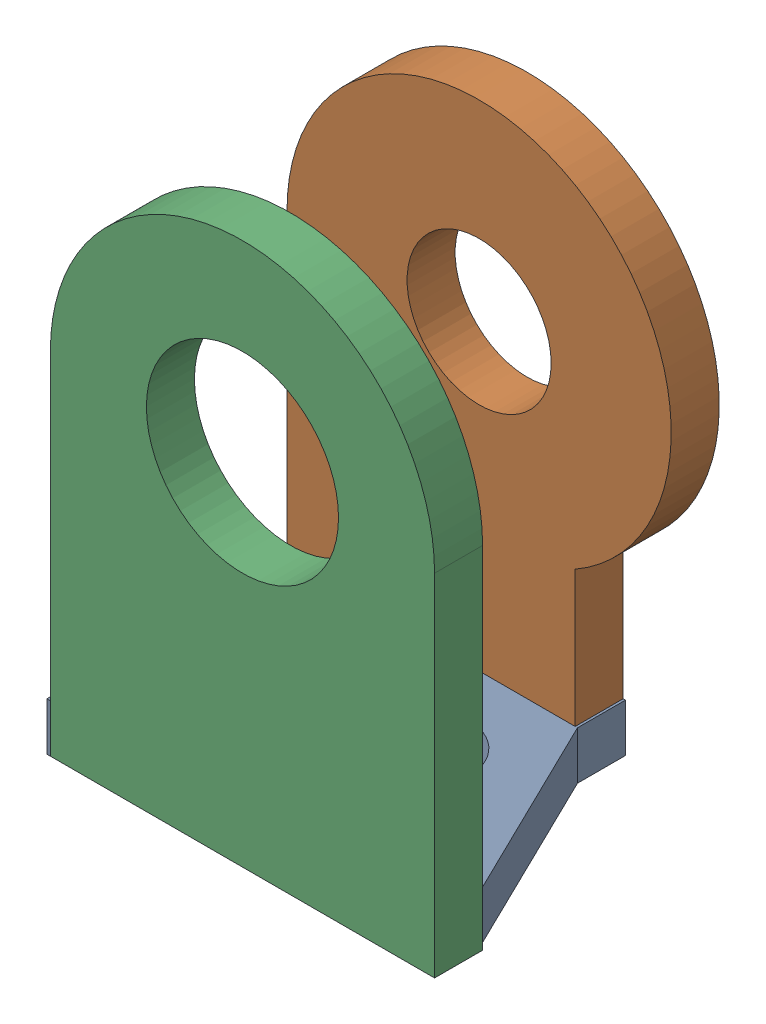
SolidWorks assembly clock_cage, configuration Default. Lengths in mm.
Overall size (25.63 35.88 19.05).
3 component instances, 3 part files, 5 mates.
Components (placement in the parent):
- clock_cage_bottom_toleranced-2: clock_cage_bottom_toleranced [Default] at (1.3815 -3.4671 1.6265) x (-1 0 0) z (0 0 -1) size (25.4 3.17 19.05)
- clock_cage_back_toleranced-2: clock_cage_back_toleranced [Default] at (-19.3061 -0.6465 -7.8985) size (25.4 35.88 3.17)
- clock_cage_front_toleranced-2: clock_cage_front_toleranced [Default] at (-19.0775 -0.6465 7.9765) size (25.4 35.88 3.17)
Mates (geometry in assembly coordinates):
- Coincident4: coincident: clock_cage_bottom_toleranced-2, clock_cage_back_toleranced-2
- Coincident7: coincident: clock_cage_bottom_toleranced-2, clock_cage_front_toleranced-2
- Coincident9: coincident: clock_cage_bottom_toleranced-2, clock_cage_front_toleranced-2
- Coincident11: coincident: clock_cage_bottom_toleranced-2, clock_cage_back_toleranced-2
- Coincident12: coincident: clock_cage_bottom_toleranced-2, clock_cage_back_toleranced-2
